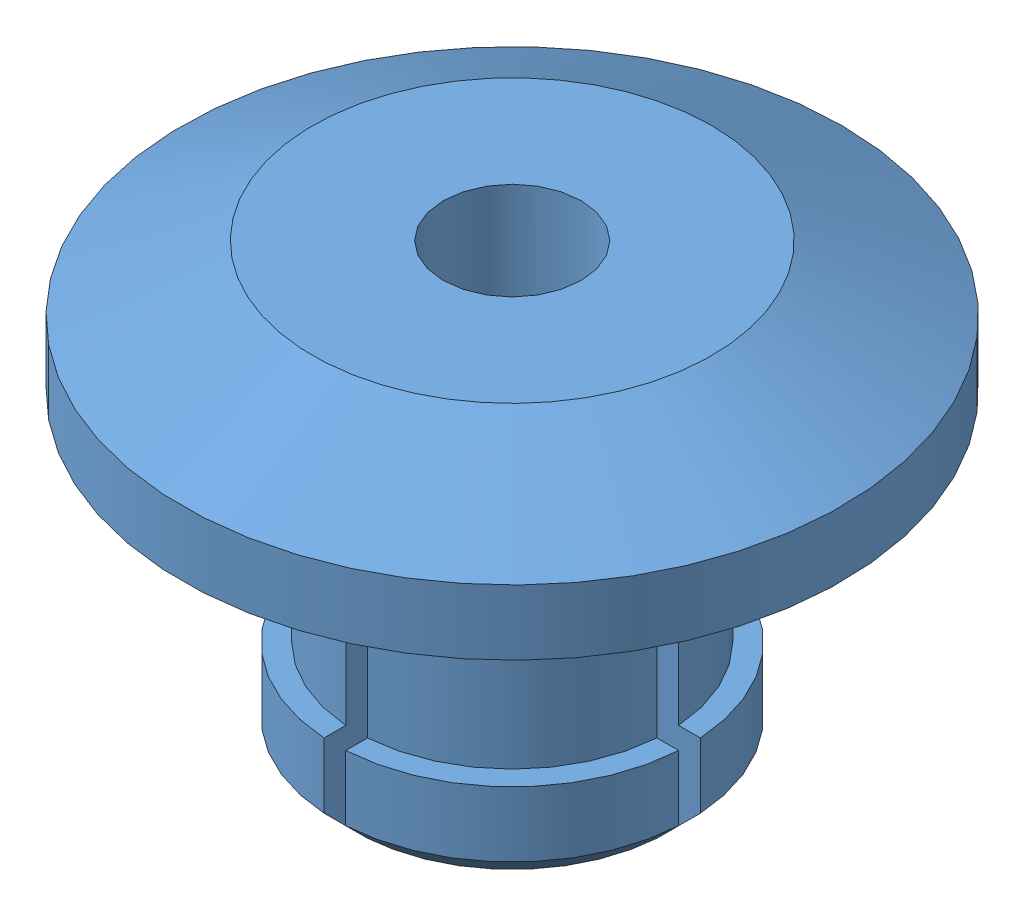
SolidWorks assembly Assemblage1, configuration Défaut. Lengths in mm.
Overall size (15.18 10 15.18).
3 component instances, 3 part files, 4 mates.
Components (placement in the parent):
- jonction exterxieure-1: jonction exterxieure [Défaut] at (-1.6616 5.6324 27.0418) size (15.18 10 15.18)
- rondelle bloquante-1: rondelle bloquante [Défaut] at (-1.6616 -1.2384 27.0418) x (1 0 0) z (0 -1 0) size (15 15 2) (hidden)
- tube flex 1_8-1: tube flex 1_8 [Défaut] at (-1.6616 4.7616 27.0418) x (0 -1 0) z (0.807237 0 0.590227) size (30 3.17 3.17) (hidden)
Mates (geometry in assembly coordinates):
- Coaxiale1: concentric: cylinder of jonction exterxieure-1 through (-1.6616 5.6324 27.0418) axis (0 -1 0) radius 1.59; cylinder of tube flex 1_8-1 through (-1.6616 -25.2384 27.0418) axis (0 1 0) radius 1.5875
- Coaxiale2: concentric anti-aligned: cylinder of jonction exterxieure-1 through (-1.6616 5.6324 27.0418) axis (0 -1 0) radius 3.59; cylinder of rondelle bloquante-1 through (-1.6616 -3.2384 27.0418) axis (0 1 0) radius 3.59
- Coïncidente1: coincident anti-aligned: plane of jonction exterxieure-1 through (1.9284 -3.2384 27.0418) normal (0 1 0); plane of rondelle bloquante-1 through (-1.6616 -3.2384 27.0418) normal (0 -1 0)
- Coïncidente2: coincident aligned: plane of jonction exterxieure-1 through (-0.0716 4.7616 27.0418) normal (0 1 0); plane of tube flex 1_8-1 through (-1.6616 4.7616 27.0418) normal (0 1 0)
